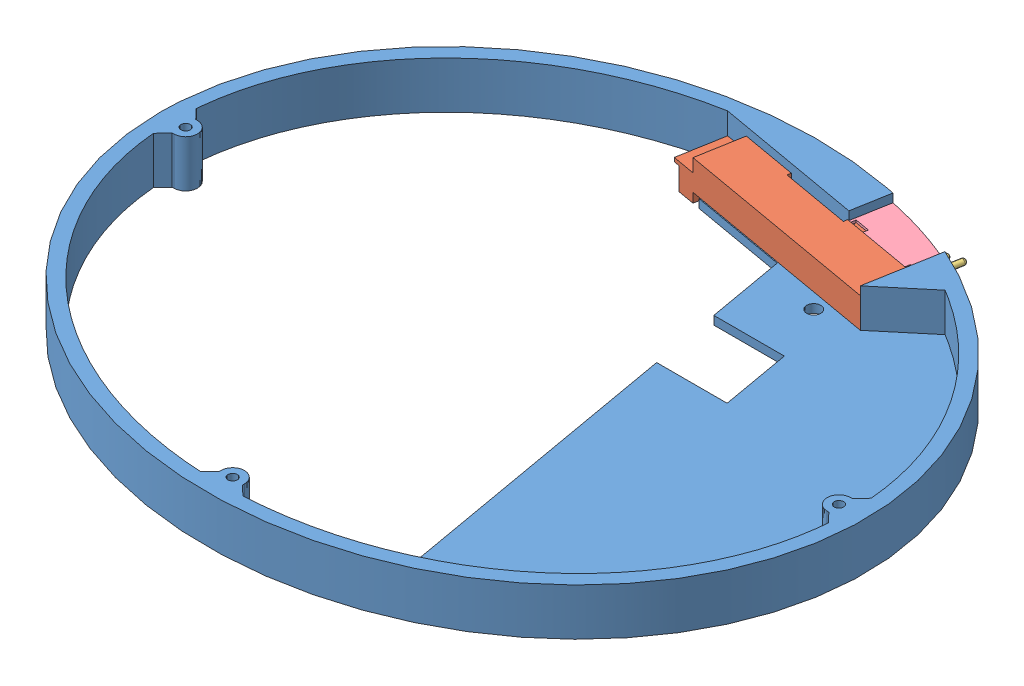
SolidWorks assembly Assem_Braille_MID, configuration Default. Lengths in mm.
Overall size (150.27 12.47 131.11).
6 component instances, 6 part files, 13 mates.
Components (placement in the parent):
- Case-UFO_MID-1: Case-UFO_MID [Default] at (55.5466 66.3432 120.3499) size (150.27 12.47 130)
- Metec_cell-2: Metec_cell [Default] at (87.0586 77.0155 77.8083) x (-0.984808 0 -0.173648) z (0 -1 0) size (48.8 10.8 8.4)
- Pins-1: Pins [Default] at (77.6265 72.5655 67.954) x (0.984808 0 0.173648) z (0 1 0) size (9.1 15.78 1.6)
- Jogget_frame-1: Jogget_frame [Default] at (55.5466 66.3432 120.3499) size (161.23 46.36 140.07) (hidden)
- Pin_cap-1: Pin_cap [Default] at (72.1923 70.6155 64.2203) x (0.984808 0 0.173648) z (-0.173648 0 0.984808) size (17 6.4 8.1)
- Pin_cap_holder-1: Pin_cap_holder [Default] at (72.4701 77.0155 62.6446) x (0.984808 0 0.173648) z (-0.173648 0 0.984808) size (17 8.2 23.5) (hidden)
Mates (geometry in assembly coordinates):
- Angle1: planar angle = 1.396263 rad anti-aligned: plane of Case-UFO_MID-1 through (55.5466 66.3432 120.3499) normal (1 0 0); plane of Metec_cell-2 through (39 70.6155 69.3342) normal (-0.173648 0 0.984808)
- Distance10: distance = 39 mm: point of assembly; plane of assembly; point of Metec_cell-2
- Coincident1: coincident: face of ?; unknown of Metec_cell-2
- Concentric1: concentric anti-aligned: cylinder of Case-UFO_MID-1 through (-13.9534 41.3422 120.3499) axis (0 1 0) radius 1; cylinder of Jogget_frame-1 through (-13.9534 106.3452 120.3499) axis (0 -1 0) radius 1
- Concentric2: concentric aligned: cylinder of Metec_cell-2 through (83.7507 72.5655 76.4127) axis (0.173648 0 -0.984808) radius 0.9; cylinder of Pins-1 through (87.4054 72.5655 55.6857) axis (0.173648 0 -0.984808) radius 0.8
- Concentric3: concentric aligned: cylinder of Metec_cell-2 through (76.3647 72.5655 75.1103) axis (0.173648 0 -0.984808) radius 0.9; cylinder of Pins-1 through (79.2935 72.5655 58.4998) axis (0.173648 0 -0.984808) radius 0.6
- Coincident10: coincident anti-aligned: plane of Case-UFO_MID-1 through (82.7509 70.6155 62.9511) normal (0 1 0); plane of Metec_cell-2 through (87.0586 70.6155 77.8083) normal (0 -1 0)
- Concentric4: concentric anti-aligned: cylinder of Metec_cell-2 through (76.3647 75.0655 75.1103) axis (0.173648 0 -0.984808) radius 0.9; cylinder of Pin_cap-1 through (79.0909 75.0655 59.6488) axis (-0.173648 0 0.984808) radius 1
- Concentric5: concentric anti-aligned: cylinder of Metec_cell-2 through (83.7507 72.5655 76.4127) axis (0.173648 0 -0.984808) radius 0.9; cylinder of Pin_cap-1 through (86.2651 72.5655 62.1526) axis (-0.173648 0 0.984808) radius 1
- Coincident12: coincident anti-aligned: plane of Case-UFO_MID-1 through (72.0186 35.8906 65.2051) normal (0.984808 0 0.173648); plane of Pin_cap_holder-1 through (75.0748 78.8155 47.8725) normal (-0.984808 0 -0.173648)
- Coincident13: coincident aligned: line of Case-UFO_MID-1 through (89.7569 70.6155 62.5057) axis (0 1 0); line of Pin_cap_holder-1 through (89.7569 77.0155 62.5057) axis (0 1 0)
- Coincident15: coincident aligned: plane of Case-UFO_MID-1 through (-19.7216 78.8155 185.3499) normal (0 1 0); plane of Pin_cap_holder-1 through (72.4701 78.8155 62.6446) normal (0 1 0)
- Coincident17: coincident anti-aligned: plane of Metec_cell-2 through (88.934 77.0155 67.1724) normal (0.173648 0 -0.984808); plane of Pin_cap-1 through (72.1923 77.0155 64.2203) normal (-0.173648 0 0.984808)
